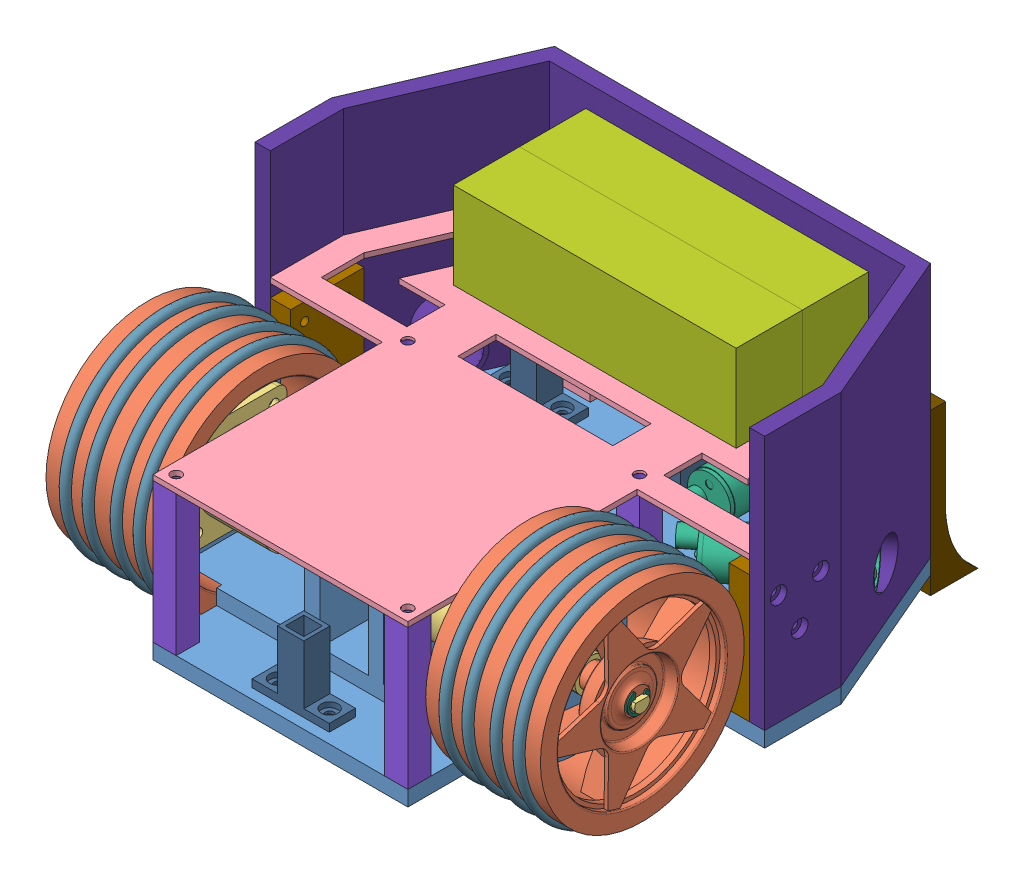
SolidWorks assembly PrototipoMejorado, configuration Predeterminado. Lengths in mm.
Overall size (200 121.32 206.06).
72 component instances, 40 part files, 151 mates.
Components (placement in the parent):
- BaseNuevaRevisado-1: BaseNuevaRevisado [Predeterminado] at (-4.5805 -14.1937 193.4559) size (200 56 181.32)
- Llanta_rueda-1: Llanta_rueda [Predeterminado] at (88.4195 37.8063 243.4559) x (1 0 0) z (0 -1 0) size (45 80 80)
- Motor-1: Motor [Predeterminado] at (92.4195 37.8063 243.4559) x (0 0 1) z (-1 0 0) size (40 40 99.5)
- Motor-2: Motor [Predeterminado] at (-101.5805 37.8063 243.4559) x (0 0 1) z (1 0 0) size (40 40 99.5)
- Llanta_rueda-2: Llanta_rueda [Predeterminado] at (-97.5805 37.8063 243.4559) x (-1 0 0) z (0 1 0) size (45 80 80)
- Base_placa-1: Base_placa [Predeterminado] at (-4.5805 62.8063 238.4559) x (-1 0 0) z (0 0 -1) size (188 2 175.32)
- PuenteH-1: PuenteH [Predeterminado] at (-4.5805 14.3063 196.4559) x (1 0 0) z (0 1 0) size (44 44 16.5)
- SensorInfrarrojo-1: SensorInfrarrojo [Predeterminado] at (80.4039 27.8063 139.2685) x (0.445413 -0.693685 0.566047) z (-0.785872 0 0.618389) size (17.5 17.5 56.83)
- SensorInfrarrojo-2: SensorInfrarrojo [Predeterminado] at (25.4195 27.8063 100.7257) x (0.999991 -0.004351 0) z (0 0 1) size (17.5 17.5 56.83)
- Pieza2^PrototipoMejorado-1: Pieza2^PrototipoMejorado [Predeterminado] x (0 0 -1) z (1 0 0) (virtual)
- Pieza3^PrototipoMejorado-1: Pieza3^PrototipoMejorado [Predeterminado] at origin (virtual)
- Bateria-1: Bateria [Predeterminado] at (-60.079 64.8063 139.131) size (111 34 26)
- Bateria-2: Bateria [Predeterminado] at (-60.079 64.8063 113.131) size (111 34 26)
- Pieza5^PrototipoMejorado-1: Pieza5^PrototipoMejorado [Predeterminado] at origin (virtual)
- Soporte-1: Soporte [Predeterminado] at (-54.5805 7.8063 288.4559) size (9.1 55 9.1)
- Soporte-4: Soporte [Predeterminado] at (45.4195 7.8063 279.3559) x (-1 0 0) z (0 0 -1) size (9.1 55 9.1)
- Soporte-5: Soporte [Predeterminado] at (-54.5805 8.7937 197.5559) size (9.1 55 9.1)
- Soporte-6: Soporte [Predeterminado] at (45.4195 8.7937 188.4559) x (-1 0 0) z (0 0 -1) size (9.1 55 9.1)
- Pieza4^PrototipoMejorado-1: Pieza4^PrototipoMejorado [Predeterminado] at origin (virtual)
- Pieza6^PrototipoMejorado-1: Pieza6^PrototipoMejorado [Predeterminado] at origin (virtual)
- Pieza7^PrototipoMejorado-1: Pieza7^PrototipoMejorado [Predeterminado] at origin (virtual)
- Pieza8^PrototipoMejorado-1: Pieza8^PrototipoMejorado [Predeterminado] at origin (virtual)
- Pieza9^PrototipoMejorado-1: Pieza9^PrototipoMejorado [Predeterminado] at origin (virtual)
- Pieza10^PrototipoMejorado-1: Pieza10^PrototipoMejorado [Predeterminado] at origin (virtual)
- Pieza11^PrototipoMejorado-1: Pieza11^PrototipoMejorado [Predeterminado] at (0 0 145.1815) (virtual)
- SensorInfrarrojo-3: SensorInfrarrojo [Predeterminado] at (-34.5805 27.8063 100.7257) x (-0.999991 -0.004351 0) z (0 0 1) size (17.5 17.5 56.83) (hidden)
- SensorInfrarrojo-4: SensorInfrarrojo [Predeterminado] at (-89.5649 27.8063 139.2685) x (-0.445413 -0.693685 0.566047) z (0.785872 0 0.618389) size (17.5 17.5 56.83) (hidden)
- Pieza12^Ensamblaje12-1: Pieza12^Ensamblaje12 [Predeterminado] at (-4.5805 7.8063 193.4559) x (1 0 0) z (0 1 0) size (8 28.77 50)
- Pieza12^Ensamblaje12-2: Pieza12^Ensamblaje12 [Predeterminado] at (-4.5805 7.8063 174.6874) x (-1 0 0) z (0 1 0) size (8 28.77 50)
- Pieza14^Ensamblaje12-1: Pieza14^Ensamblaje12 [Predeterminado] at (-4.5805 7.8063 193.4559) x (1 0 0) z (0 1 0) size (30.3 10.3 26)
- Pieza15^PrototipoMejorado-1: Pieza15^PrototipoMejorado [Predeterminado] at origin (virtual)
- Bola-1: Bola [Predeterminado] at (-56.5998 1.5563 147.4615) size (13.5 13.5 13.5)
- Bola-2: Bola [Predeterminado] at (-4.6058 1.5563 116.5872) x (0.896659 0 -0.442722) z (0.442722 0 0.896659) size (13.5 13.5 13.5)
- Bola-3: Bola [Predeterminado] at (47.4387 1.5563 147.4615) x (-1 0 0) z (0 0 -1) size (13.5 13.5 13.5)
- Pieza16^PrototipoMejorado-2: Pieza16^PrototipoMejorado [Predeterminado] at (-102.0306 0 102.0306) x (0.707107 0 0.707107) z (-0.707107 0 0.707107) (virtual)
- Pieza17^PrototipoMejorado-1: Pieza17^PrototipoMejorado [Predeterminado] at origin (virtual)
- Pieza18^PrototipoMejorado-1: Pieza18^PrototipoMejorado [Predeterminado] at origin (virtual)
- Pieza19^PrototipoMejorado-1: Pieza19^PrototipoMejorado [Predeterminado] at origin (virtual)
- Pieza20^PrototipoMejorado-1: Pieza20^PrototipoMejorado [Predeterminado] at origin (virtual)
- BolaAbajoNuevo-1: BolaAbajoNuevo [Predeterminado] at (-4.5805 1.8063 193.4559) x (-1 0 0) z (0 -1 0) size (33.75 8 5)
- BolaAbajoNuevo-3: BolaAbajoNuevo [Predeterminado] at (47.4387 1.8063 70.7152) x (1 0 0) z (0 -1 0) size (33.75 8 5)
- BolaArribaNuevo-1: BolaArribaNuevo [Predeterminado] at (-4.5805 7.8063 193.4559) x (1 0 0) z (0 1 0) size (33.75 13.75 2.8)
- BolaArribaNuevo-2: BolaArribaNuevo [Predeterminado] at (99.458 7.8063 193.4559) x (1 0 0) z (0 1 0) size (33.75 13.75 2.8)
- BolaArribaNuevo-3: BolaArribaNuevo [Predeterminado] at (47.4387 7.8063 162.704) x (1 0 0) z (0 1 0) size (33.75 13.75 2.8)
- Pieza23^Ensamblaje12-2: Pieza23^Ensamblaje12 [Predeterminado] at (-89.5805 47.7116 322.818) x (1 0 0) z (0 -0.989116 0.147135) size (4 89.79 90.42)
- Pieza23^Ensamblaje12-3: Pieza23^Ensamblaje12 [Predeterminado] at (-80.5805 47.7116 322.818) x (1 0 0) z (0 -0.989116 0.147135) size (4 89.79 90.42)
- Pieza23^Ensamblaje12-4: Pieza23^Ensamblaje12 [Predeterminado] at (-69.5805 47.7116 322.818) x (1 0 0) z (0 -0.989116 0.147135) size (4 89.79 90.42)
- Pieza23^Ensamblaje12-5: Pieza23^Ensamblaje12 [Predeterminado] at (-60.5805 47.7116 322.818) x (1 0 0) z (0 -0.989116 0.147135) size (4 89.79 90.42)
- Pieza23^Ensamblaje12-6: Pieza23^Ensamblaje12 [Predeterminado] at (88.4195 47.7116 322.818) x (1 0 0) z (0 -0.989116 0.147135) size (4 89.79 90.42)
- Pieza23^Ensamblaje12-7: Pieza23^Ensamblaje12 [Predeterminado] at (79.4195 47.7116 322.818) x (1 0 0) z (0 -0.989116 0.147135) size (4 89.79 90.42)
- Pieza23^Ensamblaje12-8: Pieza23^Ensamblaje12 [Predeterminado] at (68.4195 47.7116 322.818) x (1 0 0) z (0 -0.989116 0.147135) size (4 89.79 90.42)
- Pieza23^Ensamblaje12-9: Pieza23^Ensamblaje12 [Predeterminado] at (59.4195 47.7116 322.818) x (1 0 0) z (0 -0.989116 0.147135) size (4 89.79 90.42)
- e-ring external retaining ring_am-1: e-ring external retaining ring_am [B27.7M - 3CM1-5] at (90.4195 37.8063 243.4559) x (0 -0.27135 -0.962481) z (-1 0 0) size (8.96 7.93 0.6)
- e-ring external retaining ring_am-2: e-ring external retaining ring_am [B27.7M - 3CM1-5] at (-99.5805 37.8063 243.4559) x (0 0 -1) z (1 0 0) size (8.96 7.93 0.6)
- Pieza24^PrototipoMejorado-1: Pieza24^PrototipoMejorado [Predeterminado] at (-4.5805 7.8063 193.4559) x (1 0 0) z (0 1 0) size (5.43 43.7 11) (virtual)
- Pieza24^PrototipoMejorado-2: Pieza24^PrototipoMejorado [Predeterminado] at (34.4195 7.8063 193.4559) x (1 0 0) z (0 1 0) size (5.43 43.7 11) (virtual)
- Pieza14^Ensamblaje12-2: Pieza14^Ensamblaje12 [Predeterminado] at (51.8934 7.8063 193.4559) x (1 0 0) z (0 1 0) size (30.3 10.3 26)
- Pieza14^Ensamblaje12-3: Pieza14^Ensamblaje12 [Predeterminado] at (108.3673 7.8063 193.4559) x (1 0 0) z (0 1 0) size (30.3 10.3 26)
- Pieza14^Ensamblaje12-5: Pieza14^Ensamblaje12 [Predeterminado] at (51.8934 7.8063 341.2886) x (1 0 0) z (0 1 0) size (30.3 10.3 26)
- FrenteMejorado-1: FrenteMejorado [Predeterminado] at (-4.5805 7.8063 193.4559) x (1 0 0) z (0 1 0) size (200 91.32 100)
- Rampa-1: Rampa [Predeterminado] at (-4.5805 -14.1937 193.4559) x (0 0 -1) z (1 0 0) size (18.68 63 147.44)
- TorreAdelanteDerecha-1: TorreAdelanteDerecha [Predeterminado] at (-4.5805 7.8063 193.4559) x (1 0 0) z (0 1 0) size (27.43 8 50)
- AgarreLargo-1: AgarreLargo [Predeterminado] at (-4.5805 7.8063 110.631) x (-1 0 0) z (0 0 1) size (74.8 11.8 2.5)
- AgarreLargo-4: AgarreLargo [Predeterminado] at (-4.5805 -18.1937 110.631) x (-1 0 0) z (0 0 1) size (74.8 11.8 2.5)
- Pieza21^PrototipoMejorado-1: Pieza21^PrototipoMejorado [Predeterminado] at (-4.5805 7.8063 110.631) x (-1 0 0) z (0 0 1) size (35 12 0) (virtual)
- AlargeCorto-1: AlargeCorto [Predeterminado] at (-4.5805 7.8063 110.631) x (-1 0 0) z (0 0 1) size (34.8 11.8 2.5)
- Bola-5: Bola [Predeterminado] at (47.4387 1.5563 147.4615) x (-1 0 0) z (0 0 -1) size (13.5 13.5 13.5)
- Bola-6: Bola [Predeterminado] at (47.4387 1.5563 147.4615) x (-1 0 0) z (0 0 -1) size (13.5 13.5 13.5)
- Bola-7: Bola [Predeterminado] at (-56.5998 1.5563 147.4615) size (13.5 13.5 13.5)
- BolaAbajoNuevo-4: BolaAbajoNuevo [Predeterminado] at (-108.6191 1.8063 193.4559) x (-1 0 0) z (0 -1 0) size (33.75 8 5)
- Pieza1^PrototipoMejorado-1: Pieza1^PrototipoMejorado [Predeterminado] at (-4.5805 7.8063 193.4559) x (1 0 0) z (0 1 0) size (163.76 56.56 0) (virtual)
- TorreAdelanteIzquierda-1: TorreAdelanteIzquierda [Predeterminado] at (-4.5805 7.8063 40.8061) x (-1 0 0) z (0 1 0) size (27.43 8 50)
Mates (geometry in assembly coordinates):
- Coincidente7: coincident anti-aligned: plane of Llanta_rueda-1 through (92.4195 39.3063 243.4559) normal (0 -1 0); plane of Motor-1 through (82.4195 39.3063 246.054) normal (0 1 0)
- Coincidente8: coincident aligned: plane of BaseNuevaRevisado-1 through (-4.5805 7.8063 263.4559) normal (0 0 1); plane of Motor-1 through (57.9195 21.3063 263.4559) normal (0 0 1)
- Coincidente9: coincident anti-aligned: plane of BaseNuevaRevisado-1 through (60.4195 57.8063 223.4559) normal (-1 0 0); plane of Motor-1 through (60.4195 54.3063 259.9559) normal (1 0 0)
- Concéntrica4: concentric aligned: cylinder of BaseNuevaRevisado-1 through (-104.5815 52.3063 258.4559) axis (1 0 0) radius 2; cylinder of Motor-1 through (57.9195 52.3063 258.4559) axis (1 0 0) radius 2
- Concéntrica5: concentric anti-aligned: cylinder of Llanta_rueda-1 through (82.4195 37.8063 243.4559) axis (-1 0 0) radius 3; cylinder of Motor-1 through (72.4195 37.8063 243.4559) axis (1 0 0) radius 3
- Coincidente12: coincident anti-aligned: plane of BaseNuevaRevisado-1 through (-69.5805 57.8063 223.4559) normal (1 0 0); plane of Motor-2 through (-69.5805 21.3063 259.9559) normal (-1 0 0)
- Concéntrica8: concentric anti-aligned: cylinder of Motor-2 through (-81.5805 37.8063 243.4559) axis (-1 0 0) radius 3; cylinder of Llanta_rueda-2 through (-91.5805 37.8063 243.4559) axis (1 0 0) radius 3
- Coincidente13: coincident anti-aligned: plane of Motor-2 through (-91.5805 36.3063 246.054) normal (0 -1 0); plane of Llanta_rueda-2 through (-101.5805 36.3063 243.4559) normal (0 1 0)
- Distancia10: distance = 2 mm aligned: plane of Motor-2 through (-101.5805 37.8063 243.4559) normal (-1 0 0); plane of Llanta_rueda-2 through (-99.5805 37.8063 243.4559) normal (-1 0 0)
- Coincidente40: coincident aligned: plane of BaseNuevaRevisado-1 through (-4.5805 7.8063 288.4559) normal (0 0 1); plane of Base_placa-1 through (-4.5805 64.8063 288.4559) normal (0 0 1)
- Distancia1: distance = 55 mm anti-aligned: plane of BaseNuevaRevisado-1 through (-4.5805 7.8063 193.4559) normal (0 1 0); plane of Base_placa-1 through (-4.5805 62.8063 238.4559) normal (0 -1 0)
- Coincidente18: coincident aligned: plane of BaseNuevaRevisado-1 through (45.4195 7.8063 193.4559) normal (1 0 0); plane of Base_placa-1 through (45.4195 64.8063 238.4559) normal (1 0 0)
- EnPosición1: in place: plane of Pieza2^PrototipoMejorado-1 through (0 0 0) normal (1 0 0); moOrthogonalPlaneRef_w of Pieza2^PrototipoMejorado-1 through (0 0 0) normal (0 1 0); plane of Pieza2^PrototipoMejorado-1 through (0 0 0) normal (0 0 -1); unknown of Pieza2^PrototipoMejorado-1
- Coincidente21: coincident aligned: 
- Coincidente22: coincident aligned: plane of Pieza2^Ensamblaje12-1 through (0 0 0) normal (0 1 0)
- Coincidente23: coincident anti-aligned: plane of Pieza2^Ensamblaje12-1 through (0 0 0) normal (0 0 -1)
- Coincidente24: coincident anti-aligned: plane of Base_placa-1 through (-4.5805 64.8063 238.4559) normal (0 1 0); plane of Bateria-2 through (-60.079 64.8063 139.131) normal (0 -1 0)
- Coincidente25: coincident anti-aligned: plane of Base_placa-1 through (-4.5805 64.8063 238.4559) normal (0 1 0); plane of Bateria-1 through (-60.079 64.8063 165.131) normal (0 -1 0)
- Coincidente26: coincident aligned: plane of Bateria-1 through (50.921 64.8063 165.131) normal (1 0 0); plane of Bateria-2 through (50.921 64.8063 139.131) normal (1 0 0)
- Coincidente27: coincident anti-aligned: plane of Bateria-1 through (-60.079 64.8063 139.131) normal (0 0 -1); plane of Bateria-2 through (-60.079 64.8063 139.131) normal (0 0 1)
- Coincidente68: coincident: plane of Bateria-1 through (50.921 64.8063 165.131) normal (1 0 0); line of Frente-1 through (69.6134 106.8063 123.4732) axis (0 -1 0)
- Coincidente39: coincident anti-aligned: plane of Llanta_rueda-1 through (82.4195 37.8063 243.4559) normal (-1 0 0); plane of Motor-1 through (82.4195 37.8063 243.4559) normal (1 0 0)
- EnPosición5: in place: plane of ? through (-8.5166 0 0) normal (-1 0 0); plane of ? through (-8.5166 0 0) normal (0 1 0); plane of ? through (-8.5166 0 0) normal (0 0 1); unknown of ?
- Coincidente41: coincident aligned: 
- Coincidente42: coincident aligned: plane of Pieza1^Ensamblaje12-1 through (-4.5805 0 0) normal (0 1 0)
- Coincidente43: coincident anti-aligned: plane of Pieza1^Ensamblaje12-1 through (-4.5805 0 0) normal (0 0 1)
- Coincidente41: coincident aligned: plane of BaseNuevaRevisado-1 through (-4.5805 7.8063 263.4559) normal (0 0 1); plane of Motor-2 through (-67.0805 54.3063 263.4559) normal (0 0 1)
- Coincidente42: coincident aligned: plane of BaseNuevaRevisado-1 through (-4.5805 57.8063 193.4559) normal (0 1 0); plane of Motor-2 through (-67.0805 57.8063 259.9559) normal (0 1 0)
- Coincidente43: coincident anti-aligned: plane of Base_placa-1 through (-4.5805 62.8063 238.4559) normal (0 -1 0); plane of Soporte-1 through (-54.5805 62.8063 288.4559) normal (0 1 0)
- Coincidente44: coincident aligned: plane of BaseNuevaRevisado-1 through (-54.5805 7.8063 193.4559) normal (-1 0 0); plane of Soporte-1 through (-54.5805 62.8063 288.4559) normal (-1 0 0)
- Coincidente45: coincident aligned: plane of BaseNuevaRevisado-1 through (-4.5805 7.8063 288.4559) normal (0 0 1); plane of Soporte-1 through (-54.5805 62.8063 288.4559) normal (0 0 1)
- Concéntrica9: concentric aligned: cylinder of Base_placa-1 through (-50.0305 62.8063 193.0059) axis (0 1 0) radius 2.05; cylinder of Soporte-5 through (-50.0305 50.7937 193.0059) axis (0 1 0) radius 1.95
- Coincidente49: coincident: plane of BaseNuevaRevisado-1 through (-4.5805 1.8063 193.4559) normal (0 -1 0); plane of Pieza1^Ensamblaje12-1 through (-78.2985 1.8063 0) normal (0 -1 0)
- Concéntrica13: concentric aligned: cylinder of SensorInfrarrojo-2 through (25.4195 27.8063 148.7257) axis (0 0 -1) radius 8.75; cylinder of Pieza1^PrototipoMejorado-1 through (25.4195 27.8063 198.4569) axis (0 0 -1) radius 8.8
- Concéntrica15: concentric aligned: cylinder of SensorInfrarrojo-1 through (42.682 27.8063 168.9512) axis (0.785872 0 -0.618389) radius 8.75; cylinder of Pieza1^PrototipoMejorado-1 through (-62.6063 27.8063 251.8007) axis (0.785872 0 -0.618389) radius 8.8
- Coincidente56: coincident aligned: plane of BaseNuevaRevisado-1 through (-4.5805 1.8063 193.4559) normal (0 -1 0); plane of Frente-1 through (-78.2985 1.8063 0) normal (0 -1 0)
- Coincidente57: coincident aligned: plane of BaseNuevaRevisado-1 through (-4.5805 1.8063 193.4559) normal (0 -1 0); plane of Frente-1 through (-78.2985 1.8063 0) normal (0 -1 0)
- Coincidente58: coincident aligned: plane of Frente-1 through (-104.5805 201.8378 198.4559) normal (0 0 1); plane of BaseNuevaRevisado-1 through (-4.5805 7.8063 198.4559) normal (0 0 1)
- Coincidente59: coincident aligned: plane of Frente-1 through (95.4195 201.8378 168.4559) normal (1 0 0); plane of BaseNuevaRevisado-1 through (95.4195 7.8063 193.4559) normal (1 0 0)
- EnPosición7: in place: plane of BaseNuevaRevisado-1 through (-4.5805 7.8063 193.4559) normal (0 1 0); plane of ? through (0 7.8063 0) normal (0 1 0); plane of BaseNuevaRevisado-1 through (-4.5805 7.8063 193.4559) normal (0 1 0); plane of ? through (0 7.8063 0) normal (0 0 -1); plane of BaseNuevaRevisado-1 through (-4.5805 7.8063 193.4559) normal (0 1 0); plane of ? through (0 7.8063 0) normal (1 0 0); plane of BaseNuevaRevisado-1 through (-4.5805 7.8063 193.4559) normal (0 1 0); unknown of ?
- Coincidente62: coincident aligned: plane of ?; plane of ?
- Coincidente63: coincident aligned: moOrthogonalPlaneRef_w of BaseNuevaRevisado-1 through (-4.5805 7.8063 193.4559) normal (0 0 -1); plane of Pieza12^Ensamblaje12-1 through (-4.5805 7.8063 193.4559) normal (0 0 -1)
- Coincidente64: coincident anti-aligned: moOrthogonalPlaneRef_w of BaseNuevaRevisado-1 through (-4.5805 7.8063 193.4559) normal (-1 0 0); plane of Pieza12^Ensamblaje12-1 through (-4.5805 7.8063 193.4559) normal (1 0 0)
- EnPosición8: in place: plane of ? through (-78.2985 201.8378 107.131) normal (1 0 0); plane of ? through (-78.2985 0 0) normal (1 0 0); plane of ? through (-78.2985 201.8378 107.131) normal (1 0 0); plane of ? through (-78.2985 0 0) normal (0 1 0); plane of ? through (-78.2985 201.8378 107.131) normal (1 0 0); plane of ? through (-78.2985 0 0) normal (0 0 -1); plane of ? through (-78.2985 201.8378 107.131) normal (1 0 0); unknown of ?
- Coincidente65: coincident aligned: plane of ?; plane of ?
- Coincidente66: coincident aligned: moOrthogonalPlaneRef_w of Frente-1 through (-78.2985 0 0) normal (0 1 0); plane of Pieza13^Ensamblaje12-1 through (-78.2985 0 0) normal (0 1 0)
- Coincidente67: coincident anti-aligned: moOrthogonalPlaneRef_w of Frente-1 through (-78.2985 0 0) normal (0 0 1); plane of Pieza13^Ensamblaje12-1 through (-78.2985 0 0) normal (0 0 -1)
- Distancia7: distance = 7.75 mm anti-aligned: plane of Bateria-2 through (-60.079 64.8063 113.131) normal (0 0 -1); plane of Frente-1 through (-78.2985 0 123.4732) normal (0 0 1)
- EnPosición9: in place: plane of BaseNuevaRevisado-1 through (-4.5805 7.8063 193.4559) normal (0 1 0); plane of ? through (0 7.8063 0) normal (0 1 0); plane of BaseNuevaRevisado-1 through (-4.5805 7.8063 193.4559) normal (0 1 0); plane of ? through (0 7.8063 0) normal (0 0 -1); plane of BaseNuevaRevisado-1 through (-4.5805 7.8063 193.4559) normal (0 1 0); plane of ? through (0 7.8063 0) normal (1 0 0); plane of BaseNuevaRevisado-1 through (-4.5805 7.8063 193.4559) normal (0 1 0); unknown of ?
- Coincidente70: coincident aligned: plane of ?; plane of ?
- Coincidente71: coincident aligned: moOrthogonalPlaneRef_w of BaseNuevaRevisado-1 through (-4.5805 7.8063 193.4559) normal (0 0 -1); plane of Pieza14^Ensamblaje12-1 through (-4.5805 7.8063 193.4559) normal (0 0 -1)
- Coincidente72: coincident anti-aligned: moOrthogonalPlaneRef_w of BaseNuevaRevisado-1 through (-4.5805 7.8063 193.4559) normal (-1 0 0); plane of Pieza14^Ensamblaje12-1 through (-4.5805 7.8063 193.4559) normal (1 0 0)
- EnPosición10: in place: plane of BaseNuevaRevisado-1 through (-4.5805 7.8063 193.4559) normal (0 1 0); plane of ? through (0 7.8063 0) normal (0 1 0); plane of BaseNuevaRevisado-1 through (-4.5805 7.8063 193.4559) normal (0 1 0); plane of ? through (0 7.8063 0) normal (0 0 -1); plane of BaseNuevaRevisado-1 through (-4.5805 7.8063 193.4559) normal (0 1 0); plane of ? through (0 7.8063 0) normal (1 0 0); plane of BaseNuevaRevisado-1 through (-4.5805 7.8063 193.4559) normal (0 1 0); unknown of ?
- Coincidente73: coincident aligned: plane of ?; plane of ?
- Coincidente74: coincident aligned: moOrthogonalPlaneRef_w of BaseNuevaRevisado-1 through (-4.5805 7.8063 193.4559) normal (0 0 -1); plane of Pieza16^Ensamblaje12-1 through (-4.5805 7.8063 193.4559) normal (0 0 -1)
- Coincidente75: coincident anti-aligned: moOrthogonalPlaneRef_w of BaseNuevaRevisado-1 through (-4.5805 7.8063 193.4559) normal (-1 0 0); plane of Pieza16^Ensamblaje12-1 through (-4.5805 7.8063 193.4559) normal (1 0 0)
- Distancia8: distance = 7 mm aligned: plane of Bola-1 through (-56.5998 -5.1937 147.4615) normal (0 -1 0); plane of BaseNuevaRevisado-1 through (-4.5805 1.8063 193.4559) normal (0 -1 0)
- Concéntrica16: concentric: cylinder of BaseNuevaRevisado-1 through (-56.5998 1.8053 147.4615) axis (0 1 0) radius 6.875; sphere of Bola-1
- Tangente2: tangent aligned: cylinder of BaseNuevaRevisado-1 through (-4.5805 1.8053 116.7096) axis (0 1 0) radius 6.875; sphere of Bola-2
- Distancia9: distance = 7 mm aligned: plane of Bola-2 through (-4.6058 -5.1937 116.5872) normal (0 -1 0); plane of BaseNuevaRevisado-1 through (-4.5805 1.8063 193.4559) normal (0 -1 0)
- EnPosición11: in place: plane of Pieza16^PrototipoMejorado-2 through (-102.0306 0 102.0306) normal (-0.707107 0 0.707107); plane of Pieza16^PrototipoMejorado-2 through (-102.0306 0 102.0306) normal (0 1 0); plane of Pieza16^PrototipoMejorado-2 through (-102.0306 0 102.0306) normal (0.707107 0 0.707107); unknown of Pieza16^PrototipoMejorado-2
- Coincidente71: coincident aligned: 
- Coincidente72: coincident aligned: plane of Pieza16^Ensamblaje12-2 through (-102.0306 0 102.0306) normal (0 1 0)
- Coincidente73: coincident anti-aligned: plane of Pieza16^Ensamblaje12-2 through (-102.0306 0 102.0306) normal (0.707107 0 0.707107)
- EnPosición12: in place: plane of BaseNuevaRevisado-1 through (-4.5805 1.8063 193.4559) normal (0 -1 0); plane of ? through (0 1.8063 0) normal (0 -1 0); plane of BaseNuevaRevisado-1 through (-4.5805 1.8063 193.4559) normal (0 -1 0); plane of ? through (0 1.8063 0) normal (0 0 -1); plane of BaseNuevaRevisado-1 through (-4.5805 1.8063 193.4559) normal (0 -1 0); plane of ? through (0 1.8063 0) normal (-1 0 0); plane of BaseNuevaRevisado-1 through (-4.5805 1.8063 193.4559) normal (0 -1 0); unknown of BolaAbajoNuevo-1
- Coincidente69: coincident aligned: plane of ?; plane of ?
- Coincidente70: coincident aligned: moOrthogonalPlaneRef_w of BaseNuevaRevisado-1 through (-4.5805 1.8063 193.4559) normal (0 0 -1); plane of BolaAbajoNuevo-1 through (-4.5805 1.8063 193.4559) normal (0 0 -1)
- Coincidente71: coincident anti-aligned: moOrthogonalPlaneRef_w of BaseNuevaRevisado-1 through (-4.5805 1.8063 193.4559) normal (1 0 0); plane of BolaAbajoNuevo-1 through (-4.5805 1.8063 193.4559) normal (-1 0 0)
- Coincidente72: coincident anti-aligned: plane of BaseNuevaRevisado-1 through (-4.5805 1.8063 193.4559) normal (0 -1 0); plane of BolaAbajoNuevo-3 through (47.4387 1.8063 70.7152) normal (0 1 0)
- Coincidente73: coincident anti-aligned: circle of BaseNuevaRevisado-1; cylinder of BolaAbajoNuevo-3 through (-4.5805 -0.1937 116.7096) axis (0 1 0) radius 6.875
- Coincidente74: coincident: plane of BolaAbajoNuevo-3 through (47.4387 1.8063 116.7096) normal (0 0 -1)
- EnPosición13: in place: plane of BaseNuevaRevisado-1 through (-4.5805 7.8063 193.4559) normal (0 1 0); plane of ? through (0 7.8063 0) normal (0 1 0); plane of BaseNuevaRevisado-1 through (-4.5805 7.8063 193.4559) normal (0 1 0); plane of ? through (0 7.8063 0) normal (0 0 -1); plane of BaseNuevaRevisado-1 through (-4.5805 7.8063 193.4559) normal (0 1 0); plane of ? through (0 7.8063 0) normal (1 0 0); plane of BaseNuevaRevisado-1 through (-4.5805 7.8063 193.4559) normal (0 1 0); unknown of ?
- Coincidente75: coincident aligned: plane of ?; plane of ?
- Coincidente76: coincident aligned: moOrthogonalPlaneRef_w of BaseNuevaRevisado-1 through (-4.5805 7.8063 193.4559) normal (0 0 -1); plane of BolaArribaNuevo-1 through (-4.5805 7.8063 193.4559) normal (0 0 -1)
- Coincidente77: coincident anti-aligned: moOrthogonalPlaneRef_w of BaseNuevaRevisado-1 through (-4.5805 7.8063 193.4559) normal (-1 0 0); plane of BolaArribaNuevo-1 through (-4.5805 7.8063 193.4559) normal (1 0 0)
- Coincidente78: coincident anti-aligned: plane of BaseNuevaRevisado-1 through (-4.5805 7.8063 193.4559) normal (0 1 0); plane of BolaArribaNuevo-3 through (47.4387 7.8063 112.7096) normal (0 -1 0)
- EnPosición14: in place: plane of Llanta_rueda-2 through (-97.5805 37.8063 243.4559) normal (0 0 1); plane of ? through (-97.5805 37.8063 243.4559) normal (0 0 1); plane of Llanta_rueda-2 through (-97.5805 37.8063 243.4559) normal (0 0 1); plane of ? through (-97.5805 37.8063 243.4559) normal (0 -1 0); plane of Llanta_rueda-2 through (-97.5805 37.8063 243.4559) normal (0 0 1); plane of ? through (-97.5805 37.8063 243.4559) normal (-1 0 0); plane of Llanta_rueda-2 through (-97.5805 37.8063 243.4559) normal (0 0 1); unknown of ?
- Coincidente79: coincident aligned: plane of ?; plane of ?
- Coincidente80: coincident aligned: moOrthogonalPlaneRef_w of Llanta_rueda-2; plane of Pieza23^Ensamblaje12-1 through (-97.5805 37.8063 243.4559) normal (0 -1 0)
- Coincidente81: coincident anti-aligned: moOrthogonalPlaneRef_w of Llanta_rueda-2; plane of Pieza23^Ensamblaje12-1 through (-97.5805 37.8063 243.4559) normal (-1 0 0)
- Coincidente82: coincident anti-aligned: circle of Llanta_rueda-2; plane of Pieza23^Ensamblaje12-2 through (-95.5805 47.7116 322.818) normal (1 0 0)
- Coincidente83: coincident anti-aligned: line of Pieza23^Ensamblaje12-2 through (-135.6429 37.8063 243.4559) axis (1 0 0)
- Coincidente84: coincident anti-aligned: circle of Llanta_rueda-2; plane of Pieza23^Ensamblaje12-3 through (-86.5805 47.7116 322.818) normal (1 0 0)
- Coincidente85: coincident anti-aligned: line of Pieza23^Ensamblaje12-3 through (-126.6429 37.8063 243.4559) axis (1 0 0)
- Coincidente86: coincident anti-aligned: circle of Llanta_rueda-2; plane of Pieza23^Ensamblaje12-4 through (-75.5805 47.7116 322.818) normal (1 0 0)
- Coincidente87: coincident anti-aligned: line of Pieza23^Ensamblaje12-4 through (-115.6429 37.8063 243.4559) axis (1 0 0)
- Coincidente88: coincident anti-aligned: circle of Llanta_rueda-2; plane of Pieza23^Ensamblaje12-5 through (-66.5805 47.7116 322.818) normal (1 0 0)
- Coincidente89: coincident anti-aligned: line of Pieza23^Ensamblaje12-5 through (-106.6429 37.8063 243.4559) axis (1 0 0)
- Coincidente90: coincident anti-aligned: plane of Motor-2 through (-99.5805 37.8063 240.9559) normal (-1 0 0); plane of e-ring external retaining ring_am-2 through (-99.5805 38.3441 240.4619) normal (1 0 0)
- Concéntrica19: concentric aligned: cylinder of Motor-2 through (-81.5805 37.8063 243.4559) axis (1 0 0) radius 2.5; cylinder of e-ring external retaining ring_am-2 through (-100.1805 37.8063 243.4559) axis (1 0 0) radius 1.95
- Coincidente91: coincident anti-aligned: plane of Motor-1 through (90.4195 37.8063 240.9559) normal (1 0 0); plane of e-ring external retaining ring_am-1 through (90.4195 36.4763 240.7201) normal (-1 0 0)
- Concéntrica20: concentric aligned: cylinder of Motor-1 through (72.4195 37.8063 243.4559) axis (-1 0 0) radius 2.5; cylinder of e-ring external retaining ring_am-1 through (91.0195 37.8063 243.4559) axis (-1 0 0) radius 1.95
- Coincidente92: coincident aligned: plane of BaseNuevaRevisado-1 through (-4.5805 -14.1937 193.4559) normal (1 0 0); plane of PuenteH-1 through (-4.5805 14.3063 196.4559) normal (1 0 0)
- Distancia11: distance = 5 mm anti-aligned: plane of BaseNuevaRevisado-1 through (20.367 -14.1937 223.4559) normal (0 0 -1); plane of PuenteH-1 through (17.4195 16.3063 218.4559) normal (0 0 1)
- EnPosición15: in place: plane of BaseNuevaRevisado-1 through (-4.5805 7.8063 193.4559) normal (0 1 0); plane of ? through (0 7.8063 0) normal (0 1 0); plane of BaseNuevaRevisado-1 through (-4.5805 7.8063 193.4559) normal (0 1 0); plane of ? through (0 7.8063 0) normal (0 0 -1); plane of BaseNuevaRevisado-1 through (-4.5805 7.8063 193.4559) normal (0 1 0); plane of ? through (0 7.8063 0) normal (1 0 0); plane of BaseNuevaRevisado-1 through (-4.5805 7.8063 193.4559) normal (0 1 0); unknown of ?
- Coincidente94: coincident aligned: plane of ?; plane of ?
- Coincidente95: coincident aligned: moOrthogonalPlaneRef_w of BaseNuevaRevisado-1 through (-4.5805 7.8063 193.4559) normal (0 0 -1); plane of Pieza24^Ensamblaje12-1 through (-4.5805 7.8063 193.4559) normal (0 0 -1)
- Coincidente96: coincident anti-aligned: moOrthogonalPlaneRef_w of BaseNuevaRevisado-1 through (-4.5805 7.8063 193.4559) normal (-1 0 0); plane of Pieza24^Ensamblaje12-1 through (-4.5805 7.8063 193.4559) normal (1 0 0)
- Coincidente97: coincident anti-aligned: plane of PuenteH-1 through (-4.5805 14.3063 196.4559) normal (0 -1 0); plane of Pieza24^Ensamblaje12-1 through (-4.5805 14.3063 193.4559) normal (0 1 0)
- Coincidente100: coincident anti-aligned: plane of BaseNuevaRevisado-1 through (-4.5805 7.8063 193.4559) normal (0 1 0); plane of Pieza14^Ensamblaje12-2 through (51.8934 7.8063 193.4559) normal (0 -1 0)
- Concéntrica21: concentric anti-aligned: cylinder of BaseNuevaRevisado-1 through (-14.7305 2.8063 131.4732) axis (0 1 0) radius 1.65; cylinder of Pieza14^Ensamblaje12-2 through (-14.7305 10.8063 131.4732) axis (0 -1 0) radius 1.65
- Concéntrica22: concentric anti-aligned: cylinder of BaseNuevaRevisado-1 through (5.5695 2.8063 131.4732) axis (0 1 0) radius 1.65; cylinder of Pieza14^Ensamblaje12-2 through (5.5695 10.8063 131.4732) axis (0 -1 0) radius 1.65
- Coincidente1011: coincident anti-aligned: line of Pieza14^Ensamblaje12-2 through (10.5695 10.8063 136.6232) axis (0 0 -1); plane of Pieza14^Ensamblaje12-3 through (108.3673 10.8063 193.4559) normal (0 1 0)
- Coincidente102: coincident anti-aligned: plane of BaseNuevaRevisado-1 through (-4.5805 7.8063 193.4559) normal (0 1 0); plane of Pieza14^Ensamblaje12-3 through (108.3673 7.8063 193.4559) normal (0 -1 0)
- Concéntrica23: concentric anti-aligned: cylinder of BaseNuevaRevisado-1 through (41.7434 2.8063 131.4732) axis (0 1 0) radius 1.65; cylinder of Pieza14^Ensamblaje12-3 through (41.7434 10.8063 131.4732) axis (0 -1 0) radius 1.65
- Concéntrica24: concentric anti-aligned: cylinder of BaseNuevaRevisado-1 through (62.0434 2.8063 131.4732) axis (0 1 0) radius 1.65; cylinder of Pieza14^Ensamblaje12-3 through (62.0434 10.8063 131.4732) axis (0 -1 0) radius 1.65
- Coincidente1031: coincident anti-aligned: plane of BaseNuevaRevisado-1 through (-4.5805 7.8063 193.4559) normal (0 1 0); plane of Pieza14^Ensamblaje12-4 through (55.6719 7.8063 213.3167) normal (0 -1 0)
- Coincidente106: coincident anti-aligned: plane of BaseNuevaRevisado-1 through (-4.5805 7.8063 193.4559) normal (0 1 0); plane of Pieza14^Ensamblaje12-5 through (51.8934 7.8063 341.2886) normal (0 -1 0)
- Concéntrica25: concentric anti-aligned: cylinder of BaseNuevaRevisado-1 through (-14.7305 2.8063 279.3059) axis (0 1 0) radius 1.65; cylinder of Pieza14^Ensamblaje12-5 through (-14.7305 10.8063 279.3059) axis (0 -1 0) radius 1.65
- Concéntrica26: concentric anti-aligned: cylinder of BaseNuevaRevisado-1 through (5.5695 2.8063 279.3059) axis (0 1 0) radius 1.65; cylinder of Pieza14^Ensamblaje12-5 through (5.5695 10.8063 279.3059) axis (0 -1 0) radius 1.65
- EnPosición16: in place: plane of BaseNuevaRevisado-1 through (-4.5805 7.8063 193.4559) normal (0 1 0); plane of ? through (0 7.8063 0) normal (0 1 0); plane of BaseNuevaRevisado-1 through (-4.5805 7.8063 193.4559) normal (0 1 0); plane of ? through (0 7.8063 0) normal (0 0 -1); plane of BaseNuevaRevisado-1 through (-4.5805 7.8063 193.4559) normal (0 1 0); plane of ? through (0 7.8063 0) normal (1 0 0); plane of BaseNuevaRevisado-1 through (-4.5805 7.8063 193.4559) normal (0 1 0); unknown of ?
- Coincidente1032: coincident aligned: plane of ?; plane of ?
- Coincidente1033: coincident aligned: moOrthogonalPlaneRef_w of BaseNuevaRevisado-1 through (-4.5805 7.8063 193.4559) normal (0 0 -1); plane of Pieza1^PrototipoMejorado-1 through (-4.5805 7.8063 193.4559) normal (0 0 -1)
- Coincidente1034: coincident anti-aligned: moOrthogonalPlaneRef_w of BaseNuevaRevisado-1 through (-4.5805 7.8063 193.4559) normal (-1 0 0); plane of Pieza1^PrototipoMejorado-1 through (-4.5805 7.8063 193.4559) normal (1 0 0)
- EnPosición17: in place: plane of BaseNuevaRevisado-1 through (-4.5805 -14.1937 193.4559) normal (1 0 0); plane of Rampa-1 through (-4.5805 -14.1937 193.4559) normal (1 0 0); plane of BaseNuevaRevisado-1 through (-4.5805 -14.1937 193.4559) normal (1 0 0); plane of Rampa-1 through (-4.5805 -14.1937 193.4559) normal (0 1 0); plane of BaseNuevaRevisado-1 through (-4.5805 -14.1937 193.4559) normal (1 0 0); plane of Rampa-1 through (-4.5805 -14.1937 193.4559) normal (0 0 -1); plane of BaseNuevaRevisado-1 through (-4.5805 -14.1937 193.4559) normal (1 0 0); unknown of Rampa-1
- Coincidente1032: coincident aligned: plane of ?; plane of ?
- Coincidente1033: coincident aligned: moOrthogonalPlaneRef_w of BaseNuevaRevisado-1; plane of Pieza12^PrototipoMejorado-1 through (-4.5805 -14.1937 193.4559) normal (0 1 0)
- Coincidente1034: coincident anti-aligned: moOrthogonalPlaneRef_w of BaseNuevaRevisado-1 through (193.4559 0 0) axis (1 0 0); plane of Pieza12^PrototipoMejorado-1 through (-4.5805 -14.1937 193.4559) normal (0 0 -1)
- EnPosición18: in place: plane of BaseNuevaRevisado-1 through (-4.5805 7.8063 193.4559) normal (0 1 0); plane of ? through (0 7.8063 0) normal (0 1 0); plane of BaseNuevaRevisado-1 through (-4.5805 7.8063 193.4559) normal (0 1 0); plane of ? through (0 7.8063 0) normal (0 0 -1); plane of BaseNuevaRevisado-1 through (-4.5805 7.8063 193.4559) normal (0 1 0); plane of ? through (0 7.8063 0) normal (1 0 0); plane of BaseNuevaRevisado-1 through (-4.5805 7.8063 193.4559) normal (0 1 0); unknown of ?
- Coincidente1035: coincident aligned: plane of ?; plane of ?
- Coincidente1036: coincident aligned: moOrthogonalPlaneRef_w of BaseNuevaRevisado-1 through (-4.5805 7.8063 193.4559) normal (0 0 -1); plane of TorreAdelanteDerecha-1 through (-4.5805 7.8063 193.4559) normal (0 0 -1)
- Coincidente1037: coincident anti-aligned: moOrthogonalPlaneRef_w of BaseNuevaRevisado-1 through (-4.5805 7.8063 193.4559) normal (-1 0 0); plane of TorreAdelanteDerecha-1 through (-4.5805 7.8063 193.4559) normal (1 0 0)
- EnPosición19: in place: plane of ? through (-4.5805 7.8063 110.631) normal (0 0 1); plane of ? through (0 0 110.631) normal (0 0 1); plane of ? through (-4.5805 7.8063 110.631) normal (0 0 1); plane of ? through (0 0 110.631) normal (0 1 0); plane of ? through (-4.5805 7.8063 110.631) normal (0 0 1); plane of ? through (0 0 110.631) normal (1 0 0); plane of ? through (-4.5805 7.8063 110.631) normal (0 0 1); unknown of ?
- Coincidente1038: coincident aligned: plane of ?; plane of ?
- Coincidente1039: coincident aligned: moOrthogonalPlaneRef_w of Pieza1^PrototipoMejorado-1 through (-4.5805 7.8063 110.631) normal (0 -1 0); plane of Pieza14^PrototipoMejorado-1 through (-4.5805 7.8063 110.631) normal (0 -1 0)
- Coincidente1040: coincident anti-aligned: moOrthogonalPlaneRef_w of Pieza1^PrototipoMejorado-1 through (-4.5805 7.8063 110.631) normal (1 0 0); plane of Pieza14^PrototipoMejorado-1 through (-4.5805 7.8063 110.631) normal (-1 0 0)
- Coincidente1041: coincident anti-aligned: plane of FrenteMejorado-1 through (-4.5805 7.8063 110.631) normal (0 0 1); plane of Pieza14^PrototipoMejorado-2 through (-4.5805 -18.1937 110.631) normal (0 0 -1)
- Concéntrica27: concentric: cylinder of Pieza1^PrototipoMejorado-1 through (9.1695 57.8063 107.13) axis (0 0 1) radius 1.6; cylinder of Pieza14^PrototipoMejorado-2 through (4.1695 57.8063 113.131) axis (0 0 -1) radius 1.6
- Concéntrica28: concentric: cylinder of Pieza1^PrototipoMejorado-1 through (-18.3305 57.8063 107.13) axis (0 0 1) radius 1.6; cylinder of Pieza14^PrototipoMejorado-2 through (-13.3305 57.8063 113.131) axis (0 0 -1) radius 1.6
- Coincidente1042: coincident anti-aligned: plane of FrenteMejorado-1 through (-4.5805 7.8063 110.631) normal (0 0 1); plane of Pieza14^PrototipoMejorado-3 through (-4.5805 -44.1937 110.631) normal (0 0 -1)
- Concéntrica29: concentric anti-aligned: cylinder of Pieza1^PrototipoMejorado-1 through (4.1695 31.8063 107.13) axis (0 0 1) radius 1.6; cylinder of Pieza14^PrototipoMejorado-3 through (4.1695 31.8063 113.131) axis (0 0 -1) radius 1.6
- Coincidente1043: coincident aligned: cylinder of Pieza1^PrototipoMejorado-1 through (-27.0805 57.8063 107.13) axis (0 0 1) radius 1.6; circle of Pieza14^PrototipoMejorado-4
- Coincidente1044: coincident anti-aligned: plane of Pieza1^PrototipoMejorado-1 through (-4.5805 7.8063 110.631) normal (0 0 1); plane of Pieza14^PrototipoMejorado-4 through (-4.5805 -18.1937 110.631) normal (0 0 -1)
- Concéntrica30: concentric aligned: cylinder of Pieza1^PrototipoMejorado-1 through (17.9195 57.8063 107.13) axis (0 0 1) radius 1.6; cylinder of Pieza14^PrototipoMejorado-4 through (17.9195 57.8063 110.63) axis (0 0 1) radius 1.6
- EnPosición20: in place: plane of ? through (-4.5805 7.8063 110.631) normal (0 0 1); plane of ? through (0 0 110.631) normal (0 0 1); plane of ? through (-4.5805 7.8063 110.631) normal (0 0 1); plane of ? through (0 0 110.631) normal (0 1 0); plane of ? through (-4.5805 7.8063 110.631) normal (0 0 1); plane of ? through (0 0 110.631) normal (1 0 0); plane of ? through (-4.5805 7.8063 110.631) normal (0 0 1); unknown of ?
- Coincidente1045: coincident aligned: plane of ?; plane of ?
- Coincidente1046: coincident aligned: moOrthogonalPlaneRef_w of Pieza1^PrototipoMejorado-1 through (-4.5805 7.8063 110.631) normal (0 -1 0); plane of Pieza21^PrototipoMejorado-1 through (-4.5805 7.8063 110.631) normal (0 -1 0)
- Coincidente1047: coincident anti-aligned: moOrthogonalPlaneRef_w of Pieza1^PrototipoMejorado-1 through (-4.5805 7.8063 110.631) normal (1 0 0); plane of Pieza21^PrototipoMejorado-1 through (-4.5805 7.8063 110.631) normal (-1 0 0)
- EnPosición21: in place: plane of ? through (-4.5805 7.8063 110.631) normal (0 0 1); plane of ? through (0 0 110.631) normal (0 0 1); plane of ? through (-4.5805 7.8063 110.631) normal (0 0 1); plane of ? through (0 0 110.631) normal (0 1 0); plane of ? through (-4.5805 7.8063 110.631) normal (0 0 1); plane of ? through (0 0 110.631) normal (1 0 0); plane of ? through (-4.5805 7.8063 110.631) normal (0 0 1); unknown of ?
- Coincidente1048: coincident aligned: plane of ?; plane of ?
- Coincidente1049: coincident aligned: moOrthogonalPlaneRef_w of Pieza1^PrototipoMejorado-1 through (-4.5805 7.8063 110.631) normal (0 -1 0); plane of Pieza22^PrototipoMejorado-1 through (-4.5805 7.8063 110.631) normal (0 -1 0)
- Coincidente1050: coincident anti-aligned: moOrthogonalPlaneRef_w of Pieza1^PrototipoMejorado-1 through (-4.5805 7.8063 110.631) normal (1 0 0); plane of Pieza22^PrototipoMejorado-1 through (-4.5805 7.8063 110.631) normal (-1 0 0)
- EnPosición22: in place: plane of BaseNuevaRevisado-1 through (-4.5805 7.8063 193.4559) normal (0 1 0); plane of ? through (0 7.8063 0) normal (0 1 0); plane of BaseNuevaRevisado-1 through (-4.5805 7.8063 193.4559) normal (0 1 0); plane of ? through (0 7.8063 0) normal (0 0 -1); plane of BaseNuevaRevisado-1 through (-4.5805 7.8063 193.4559) normal (0 1 0); plane of ? through (0 7.8063 0) normal (1 0 0); plane of BaseNuevaRevisado-1 through (-4.5805 7.8063 193.4559) normal (0 1 0); unknown of ?
- Coincidente1045: coincident aligned: plane of ?; plane of ?
- Coincidente1046: coincident aligned: moOrthogonalPlaneRef_w of BaseNuevaRevisado-1 through (-4.5805 7.8063 193.4559) normal (0 0 -1); plane of Pieza1^PrototipoMejorado-1 through (-4.5805 7.8063 193.4559) normal (0 0 -1)
- Coincidente1047: coincident anti-aligned: moOrthogonalPlaneRef_w of BaseNuevaRevisado-1 through (-4.5805 7.8063 193.4559) normal (-1 0 0); plane of Pieza1^PrototipoMejorado-1 through (-4.5805 7.8063 193.4559) normal (1 0 0)
- Coincidente1046: coincident anti-aligned: plane of FrenteMejorado-1 through (-74.3421 107.8063 113.131) normal (0 0 1); plane of TorreAdelanteIzquierda-1 through (-50.3421 86.3778 113.131) normal (0 0 -1)
- Concéntrica31: concentric anti-aligned: cylinder of Rampa-1 through (-56.3421 42.8063 100.731) axis (0 0 1) radius 1.6; cylinder of TorreAdelanteIzquierda-1 through (-56.3421 42.8063 121.132) axis (0 0 -1) radius 1.6
- Coincidente1047: coincident anti-aligned: plane of BaseNuevaRevisado-1 through (-4.5805 7.8063 193.4559) normal (0 1 0); plane of TorreAdelanteIzquierda-1 through (-4.5805 7.8063 40.8061) normal (0 -1 0)
- Coincidente1048: coincident anti-aligned: plane of Bateria-2 through (-60.079 64.8063 113.131) normal (0 0 -1); plane of FrenteMejorado-1 through (-74.3421 107.8063 113.131) normal (0 0 1)
- Distancia12: distance = 14.26 mm: plane of Bateria-2 through (50.921 64.8063 139.131) normal (1 0 0); line of FrenteMejorado-1 through (65.181 107.8063 113.131) axis (0 -1 0)
